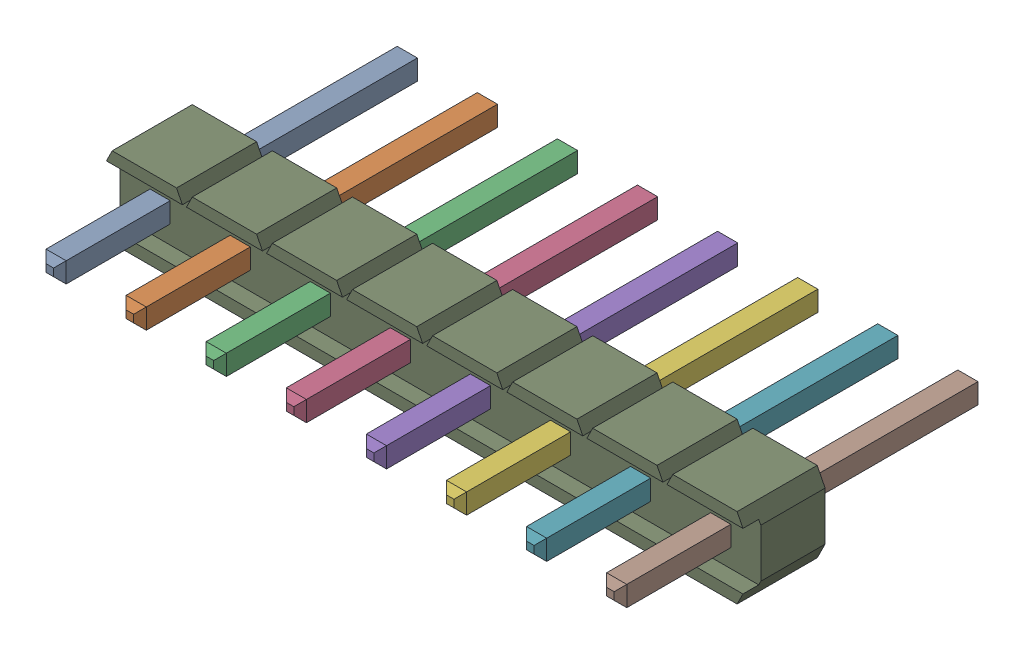
SolidWorks assembly C2_1, configuration Default. Lengths in mm.
Overall size (20.32 2.54 11.54).
10 component instances, 2 part files, 0 mates.
Components (placement in the parent):
- 61300811121-1: 61300811121 [Default] at (23.5001 3.4999 -1.6815) x (1 0 0) z (0 1 0) size (20.32 11.54 2.54)
  - 6130xx11121_PIN_2-1: 6130xx11121_PIN_2 [Default] at (-8.89 1.5 0) x (1 0 0) z (0 -1 0) size (0.64 0.64 11.54)
  - 6130xx11121_PIN_2-2: 6130xx11121_PIN_2 [Default] at (-6.35 1.5 0) x (1 0 0) z (0 -1 0) size (0.64 0.64 11.54)
  - 6130xx11121_PIN_2-3: 6130xx11121_PIN_2 [Default] at (-3.81 1.5 0) x (1 0 0) z (0 -1 0) size (0.64 0.64 11.54)
  - 6130xx11121_PIN_2-4: 6130xx11121_PIN_2 [Default] at (-1.27 1.5 0) x (1 0 0) z (0 -1 0) size (0.64 0.64 11.54)
  - 6130xx11121_PIN_2-5: 6130xx11121_PIN_2 [Default] at (1.27 1.5 0) x (1 0 0) z (0 -1 0) size (0.64 0.64 11.54)
  - 6130xx11121_PIN_2-6: 6130xx11121_PIN_2 [Default] at (3.81 1.5 0) x (1 0 0) z (0 -1 0) size (0.64 0.64 11.54)
  - 6130xx11121_PIN_2-7: 6130xx11121_PIN_2 [Default] at (6.35 1.5 0) x (1 0 0) z (0 -1 0) size (0.64 0.64 11.54)
  - 6130xx11121_PIN_2-8: 6130xx11121_PIN_2 [Default] at (8.89 1.5 0) x (1 0 0) z (0 -1 0) size (0.64 0.64 11.54)
  - 61300811121-1: 61300811121 [Default] at origin size (20.32 2.54 2.54)
